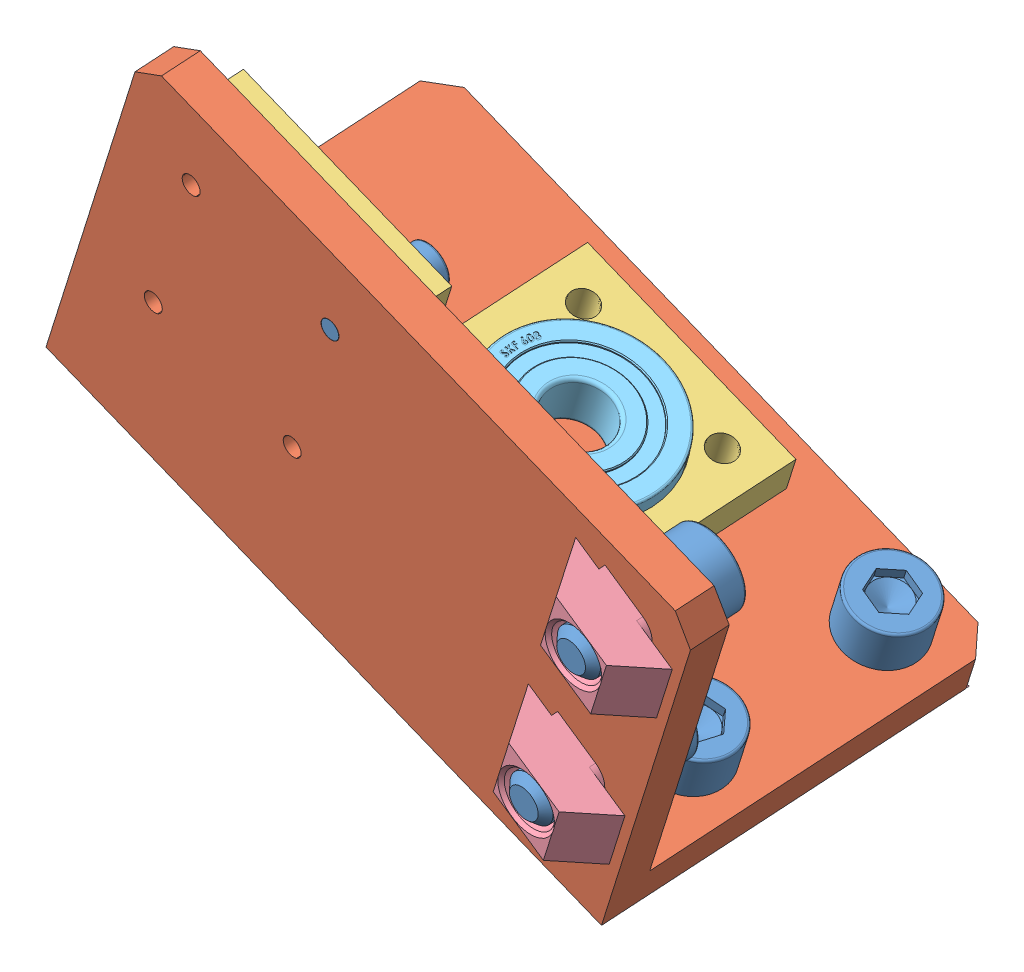
SolidWorks assembly Support plate 50x50 L.80mm Front-Left, configuration Default. Lengths in mm.
Overall size (94.93 86.23 62.25).
21 component instances, 5 part files, 23 mates.
Components (placement in the parent):
- Socket head cap screw-27: Socket head cap screw [M3x14] at (16.1735 -40.6295 79.1481) x (-0.043667 -0.108723 0.993113) z (0.363822 0.924071 0.117162) size (17 5.5 5.5)
- Socket head cap screw-28: Socket head cap screw [M3x14] at (-9.7881 -51.6068 76.8048) x (-0.043667 -0.108723 0.993113) z (0.363822 0.924071 0.117162) size (17 5.5 5.5)
- Socket head cap screw-29: Socket head cap screw [M3x14] at (25.918 -70.0301 49.1706) x (-0.370131 -0.921561 -0.117164) z (0.722911 -0.206518 -0.659356) size (17 5.5 5.5)
- Socket head cap screw-39: Socket head cap screw [M3x14] at (7.359 -62.5761 49.1706) x (-0.370131 -0.921561 -0.117164) z (-0.022568 -0.117164 0.992856) size (17 5.5 5.5)
- Socket head cap screw-42: Socket head cap screw [M3x14] at (6.4857 -64.7506 69.0329) x (-0.370131 -0.921561 -0.117164) z (-0.022568 -0.117164 0.992856) size (17 5.5 5.5)
- Socket head cap screw-44: Socket head cap screw [M3x14] at (-2.3855 -33.1755 79.1481) x (-0.043667 -0.108723 0.993113) z (0.363822 0.924071 0.117162) size (17 5.5 5.5)
- Socket head cap screw-41: Socket head cap screw [M3x14] at (8.7709 -59.0607 76.8048) x (-0.043667 -0.108723 0.993113) z (0.363822 0.924071 0.117162) size (17 5.5 5.5)
- Socket head cap screw-38: Socket head cap screw [M3x14] at (25.0447 -72.2046 69.0329) x (-0.370131 -0.921561 -0.117164) z (-0.022568 -0.117164 0.992856) size (17 5.5 5.5)
- Support plate 50x50 L.80mm Front-Left-1: Support plate 50x50 L.80mm Front-Left [Default] at (-27.038 -67.7244 87.372) x (0.043667 0.108723 -0.993113) z (0.927953 -0.372698 0) size (50 50 80)
- Bearing Housing-1: Bearing Housing [Default] at (15.0915 -70.155 58.7503) x (0.927953 -0.372698 0) z (-0.370131 -0.921561 -0.117164) size (30 30 5)
- Bearing Housing-2: Bearing Housing [Default] at (3.0617 -46.4443 80.9558) x (0.927953 -0.372698 0) z (-0.043667 -0.108723 0.993113) size (30 30 5)
- HNTF6-6-15: HNTF6-6 [Default] at (46.0494 -78.9356 89.761) x (0.043667 0.108723 -0.993113) z (-0.370131 -0.921561 -0.117164) size (6.53 15 12.3)
- HNTF6-6-14: HNTF6-6 [Default] at (41.4606 -90.3609 45.6144) x (0.370131 0.921561 0.117164) z (-0.043667 -0.108723 0.993113) size (6.53 15 12.3)
- HNTF6-6-13: HNTF6-6 [Default] at (40.3689 -93.079 70.4422) x (0.370131 0.921561 0.117164) z (-0.043667 -0.108723 0.993113) size (6.53 15 12.3)
- HNTF6-6-12: HNTF6-6 [Default] at (55.3027 -55.8966 92.6901) x (0.043667 0.108723 -0.993113) z (-0.370131 -0.921561 -0.117164) size (6.53 15 12.3)
- Socket head cap screw-43: Socket head cap screw [M6x12] at (45.6801 -79.8551 46.9501) x (-0.370131 -0.921561 -0.117164) z (0.882088 -0.309079 -0.355515) size (18 10 10)
- Socket head cap screw-45: Socket head cap screw [M6x12] at (44.5884 -82.5732 71.7779) x (-0.370131 -0.921561 -0.117164) z (-0.882545 0.388198 -0.265361) size (18 10 10)
- Socket head cap screw-37: Socket head cap screw [M6x12] at (46.5472 -77.6962 78.4395) x (-0.043667 -0.108723 0.993113) z (-0.993113 0.112904 -0.031307) size (18 10 10)
- Socket head cap screw-40: Socket head cap screw [M6x12] at (55.8005 -54.6572 81.3687) x (-0.043667 -0.108723 0.993113) z (-0.993113 0.112904 -0.031307) size (18 10 10)
- 8mm Bearing SKF 608 RS 286-7530-1: 8mm Bearing SKF 608 RS 286-7530 [Default] at (15.8317 -68.3119 58.9846) x (0.370131 0.921561 0.117164) z (-0.117164 -0.078806 0.989981) size (7 22 22)
- 8mm Bearing SKF 608 RS 286-7530-2: 8mm Bearing SKF 608 RS 286-7530 [Default] at (3.149 -46.2269 78.9696) x (0.043667 0.108723 -0.993113) z (0.993113 0.103457 0.054993) size (7 22 22)
Mates (geometry in assembly coordinates):
- Coincidente60: coincident: plane of Socket head cap screw-29 through (23.2032 -71.8907 46.7769) normal (-0.370131 -0.921561 -0.117164); plane of Socket head cap screw-38 through (26.4883 -75.9871 68.6193) normal (-0.370131 -0.921561 -0.117164)
- Coincidente61: coincident: plane of Socket head cap screw-29 through (23.2032 -71.8907 46.7769) normal (-0.370131 -0.921561 -0.117164); plane of Socket head cap screw-42 through (7.9292 -68.5331 68.6193) normal (-0.370131 -0.921561 -0.117164)
- Coincidente64: coincident: plane of Socket head cap screw-41 through (11.1986 -60.3946 79.7863) normal (-0.043667 -0.108723 0.993113); plane of Socket head cap screw-44 through (0.0422 -34.5094 82.1296) normal (-0.043667 -0.108723 0.993113)
- Coincidente65: coincident: plane of Socket head cap screw-41 through (11.1986 -60.3946 79.7863) normal (-0.043667 -0.108723 0.993113); plane of Socket head cap screw-28 through (-7.3604 -52.9406 79.7863) normal (-0.043667 -0.108723 0.993113)
- Coincidente66: coincident anti-aligned: plane of Support plate 50x50 L.80mm Front-Left-1 through (49.2672 -92.3889 82.9922) normal (0.370131 0.921561 0.117164); plane of Bearing Housing-1 through (13.2408 -74.7628 58.1644) normal (-0.370131 -0.921561 -0.117164)
- Coincidente71: coincident aligned: circle of Socket head cap screw-27; plane of Bearing Housing-2 through (3.0617 -46.4443 80.9558) normal (0.043667 0.108723 -0.993113)
- Concentric1: concentric anti-aligned: cylinder of Support plate 50x50 L.80mm Front-Left-1 through (41.6086 -89.9923 45.6613) axis (-0.370131 -0.921561 -0.117164) radius 3.25; cylinder of Socket head cap screw-43 through (57.4317 -50.5956 50.67) axis (0.370131 0.921561 0.117164) radius 3
- Concentric2: concentric anti-aligned: cylinder of Support plate 50x50 L.80mm Front-Left-1 through (40.517 -92.7104 70.4891) axis (-0.370131 -0.921561 -0.117164) radius 3.25; cylinder of Socket head cap screw-45 through (56.3401 -53.3136 75.4979) axis (0.370131 0.921561 0.117164) radius 3
- Coincident2: coincident aligned: plane of Support plate 50x50 L.80mm Front-Left-1 through (49.2672 -92.3889 82.9922) normal (0.370131 0.921561 0.117164); circle of Socket head cap screw-45
- Concentric4: concentric anti-aligned: cylinder of Support plate 50x50 L.80mm Front-Left-1 through (46.0669 -78.8921 89.3638) axis (-0.043667 -0.108723 0.993113) radius 3.25; cylinder of Socket head cap screw-37 through (47.9336 -74.2442 46.9082) axis (0.043667 0.108723 -0.993113) radius 3
- Concentric5: concentric anti-aligned: cylinder of Support plate 50x50 L.80mm Front-Left-1 through (55.3201 -55.8531 92.2929) axis (-0.043667 -0.108723 0.993113) radius 3.25; cylinder of Socket head cap screw-40 through (57.1869 -51.2052 49.8373) axis (0.043667 0.108723 -0.993113) radius 3
- Coincident5: coincident anti-aligned: plane of Support plate 50x50 L.80mm Front-Left-1 through (49.2672 -92.3889 82.9922) normal (0.370131 0.921561 0.117164); plane of 8mm Bearing SKF 608 RS 286-7530-1 through (5.4029 -71.5297 57.4942) normal (-0.370131 -0.921561 -0.117164)
- Concentric6: concentric aligned: cylinder of Bearing Housing-1 through (13.2408 -74.7628 58.1644) axis (0.370131 0.921561 0.117164) radius 11; cylinder of 8mm Bearing SKF 608 RS 286-7530-1 through (15.8317 -68.3119 58.9846) axis (0.370131 0.921561 0.117164) radius 11
- Coincident6: coincident anti-aligned: plane of Support plate 50x50 L.80mm Front-Left-1 through (65.9231 -50.9186 88.2646) normal (0.043667 0.108723 -0.993113); plane of 8mm Bearing SKF 608 RS 286-7530-2 through (1.9187 -38.5792 86.8013) normal (-0.043667 -0.108723 0.993113)
- Concentric7: concentric aligned: cylinder of Bearing Housing-2 through (2.8434 -46.9879 85.9214) axis (0.043667 0.108723 -0.993113) radius 11; cylinder of 8mm Bearing SKF 608 RS 286-7530-2 through (3.149 -46.2269 78.9696) axis (0.043667 0.108723 -0.993113) radius 11
- Concentric8: concentric anti-aligned: cylinder of HNTF6-6-12 through (55.0276 -56.5816 98.9467) axis (-0.043667 -0.108723 0.993113) radius 3.5; cylinder of Socket head cap screw-40 through (57.1869 -51.2052 49.8373) axis (0.043667 0.108723 -0.993113) radius 3
- Parallel1: parallel anti-aligned: plane of Support plate 50x50 L.80mm Front-Left-1 through (47.1982 -97.5403 87.372) normal (0.927953 -0.372698 0); plane of HNTF6-6-12 through (51.2412 -55.5447 93.3556) normal (-0.927953 0.372698 0)
- Concentric9: concentric anti-aligned: cylinder of HNTF6-6-15 through (45.7743 -79.6206 96.0176) axis (-0.043667 -0.108723 0.993113) radius 3.5; cylinder of Socket head cap screw-37 through (47.9336 -74.2442 46.9082) axis (0.043667 0.108723 -0.993113) radius 3
- Parallel2: parallel anti-aligned: plane of Support plate 50x50 L.80mm Front-Left-1 through (47.1982 -97.5403 87.372) normal (0.927953 -0.372698 0); plane of HNTF6-6-15 through (41.9879 -78.5838 90.4265) normal (-0.927953 0.372698 0)
- Concentric10: concentric anti-aligned: cylinder of HNTF6-6-13 through (38.0371 -98.8849 69.7041) axis (-0.370131 -0.921561 -0.117164) radius 3.5; cylinder of Socket head cap screw-45 through (56.3401 -53.3136 75.4979) axis (0.370131 0.921561 0.117164) radius 3
- Parallel3: parallel anti-aligned: plane of Support plate 50x50 L.80mm Front-Left-1 through (47.1982 -97.5403 87.372) normal (0.927953 -0.372698 0); plane of HNTF6-6-13 through (36.5019 -92.243 69.255) normal (-0.927953 0.372698 0)
- Concentric11: concentric anti-aligned: cylinder of HNTF6-6-14 through (39.1287 -96.1668 44.8763) axis (-0.370131 -0.921561 -0.117164) radius 3.5; cylinder of Socket head cap screw-43 through (57.4317 -50.5956 50.67) axis (0.370131 0.921561 0.117164) radius 3
- Parallel4: parallel anti-aligned: plane of Support plate 50x50 L.80mm Front-Left-1 through (47.1982 -97.5403 87.372) normal (0.927953 -0.372698 0); plane of HNTF6-6-14 through (37.5935 -89.525 44.4272) normal (-0.927953 0.372698 0)
